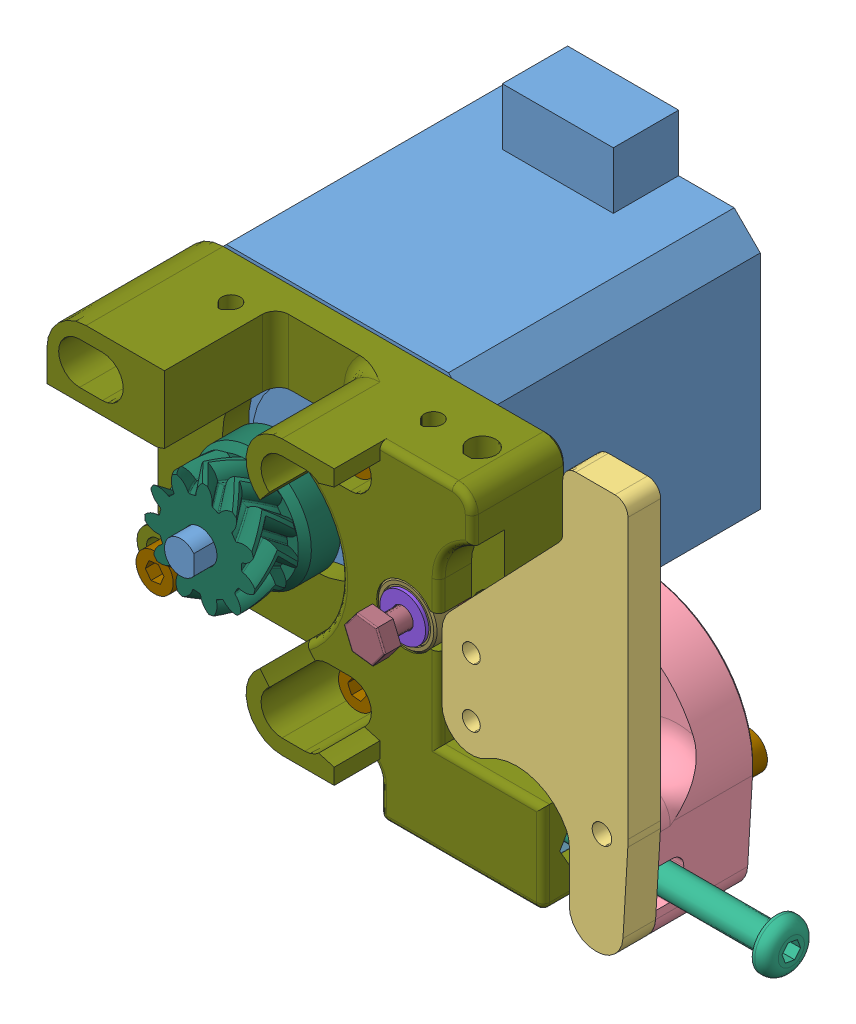
SolidWorks assembly extruder-drive, configuration Default. Lengths in mm.
Overall size (102.01 62 67.75).
27 component instances, 17 part files, 60 mates.
Components (placement in the parent):
- 408-1: 408 [Default] at (-0.1298 7.2239 -17.7265) x (0 -1 0) z (0 0 1) size (50.7 42 67.75)
- 279-1: 279 [Default] at (33.8857 6.1479 32.8235) x (0.656358 0.75445 0) z (0 0 -1) size (10 10 4)
- 1308-1: 1308 [lasercut] at (34.8702 7.2796 40.5235) x (1 0 0) z (0 0 -1) size (28.5 62 5)
- 1309-2: 1309 [Default] at (34.8702 7.2796 29.0235) x (1 0 0) z (0 0 -1) size (28.5 35.3 14.5)
- 1193-1: 1193 [Default] at (39.681 -14.7761 33.5235) x (0 0.866025 -0.5) z (1 0 0) size (8.08 7 3.2)
- 650-1: 650 [Default] at (74.681 -14.7761 33.5235) x (0 -0.641308 -0.767284) z (1 0 0) size (7.6 7.6 37.2)
- 1185-2: 1185 [Default] at (49.0702 -14.7761 33.5235) x (0 -0.672385 0.740201) z (1 0 0) size (9 9 0.8)
- 212-2: 212 [Default] at (34.8702 7.2796 35.8235) x (0.728607 0.684932 0) z (0 0 -1) size (7 7 0.5)
- 257-6: 257 [Default] at (34.8702 7.2796 21.0235) x (0.881615 -0.471969 0) z (0 0 -1) size (5.7 5.7 15)
- 1183-1: 1183 [Default] at (5.8702 7.2239 29.13) x (-1 0 0) z (0 -0.924225 -0.381849) size (4 3 3)
- 212-4: 212 [Default] at (24.8702 7.2239 26.1235) x (0.64125 0.767332 0) z (0 0 -1) size (7 7 0.5)
- 212-5: 212 [Default] at (34.8702 7.2796 31.3235) x (0.728607 0.684932 0) z (0 0 -1) size (7 7 0.5)
- 448-1: 448 [Default] at (24.8702 7.2239 30.1235) size (8.22 8.21 6.4)
- 423-2: 423 [Default] at (24.8702 7.2239 39.0235) x (0.994247 0.107114 0) z (0 0 1) size (9 9 4)
- 423-3: 423 [Default] at (24.8702 7.2239 28.6235) x (-0.824305 -0.566147 0) z (0 0 1) size (9 9 4)
- 113-1: 113 [Default] at (24.8702 7.2239 44.4235) x (-0.991951 0.126624 0) z (0 0 1) size (6.35 5.5 27.5)
- 204-1: 204 [Default] at (24.8702 7.2239 25.6235) x (0.98296 -0.183817 0) z (0 0 -1) size (6.35 5.5 4)
- 1310-4: 1310 [ISO - RH Helical gear 1M 17T 45HA 20PA 12FW ---17A75H50L0.8N] at (-0.1298 7.2239 43.5235) x (0 0 -1) z (0.449096 -0.893483 0) size (13 18 18)
- 1311-4: 1311 [ISO - RH Helical gear 1M 17T 45HA 20PA 12FW ---17A75H50L0.8N] at (24.8702 7.2239 47.0235) x (0 0 -1) z (0.991951 -0.126624 0) size (9 36.33 36.3) (hidden)
- 1306-1: 1306 [Default] at (-0.1298 7.2239 26.0235) x (0 -1 0) z (0 0 1) size (50 69 21.5)
- 257-7: 257 [Default] at (34.8702 -1.7204 21.0235) x (-0.999483 0.032148 0) z (0 0 -1) size (5.7 5.7 15)
- 257-8: 257 [Default] at (54.8702 -6.7204 21.0235) x (-0.827471 0.561509 0) z (0 0 -1) size (5.7 5.7 15)
- 257-9: 257 [Default] at (-15.6298 22.7239 35.5235) x (0.910936 0.412547 0) z (0 0 1) size (5.7 5.7 15)
- 257-10: 257 [Default] at (15.3702 -8.2761 35.5235) x (0.910936 0.412547 0) z (0 0 1) size (5.7 5.7 15)
- 257-11: 257 [Default] at (15.3702 22.7239 35.5235) x (0.910936 0.412547 0) z (0 0 1) size (5.7 5.7 15)
- 257-12: 257 [Default] at (-15.6298 -8.2761 35.5235) x (-0.129262 0.991611 0) z (0 0 1) size (5.7 5.7 15)
- 212-6: 212 [Default] at (24.8702 7.2239 41.0235) x (0.728607 0.684932 0) z (0 0 -1) size (7 7 0.5)
Mates (geometry in assembly coordinates):
- Concentric1: concentric aligned: cylinder of 408-1 through (-0.1298 7.2239 50.0235) axis (0 0 -1) radius 2.5; cylinder of 1310-4 through (-0.1298 7.2239 47.0235) axis (0 0 -1) radius 2.55
- Coincident59: coincident aligned: plane of 1310-4 through (-0.1298 7.2239 47.0235) normal (0 0 1); plane of 1311-4 through (24.8702 7.2239 47.0235) normal (0 0 1)
- Parallel9: parallel anti-aligned: plane of 113-1 through (26.7934 9.7507 46.9235) normal (0.126624 0.991951 0); plane of 1311-4 through (23.5989 10.2593 44.4235) normal (-0.126624 -0.991951 0)
- Concentric2: concentric aligned: cylinder of 113-1 through (24.8702 7.2239 19.4235) axis (0 0 1) radius 1.5; cylinder of 1311-4 through (24.8702 7.2239 41.0235) axis (0 0 1) radius 1.65
- Coincident61: coincident anti-aligned: plane of 113-1 through (24.8702 7.2239 44.4235) normal (0 0 -1); plane of 1311-4 through (24.8702 7.2239 44.4235) normal (0 0 1)
- Concentric3: concentric aligned: cylinder of 113-1 through (24.8702 7.2239 19.4235) axis (0 0 1) radius 1.5; cylinder of 204-1 through (24.8702 7.2239 23.2235) axis (0 0 1) radius 1.25
- Concentric5: concentric anti-aligned: cylinder of 423-2 through (24.8702 7.2239 41.5235) axis (0 0 -1) radius 1.5; cylinder of 113-1 through (24.8702 7.2239 19.4235) axis (0 0 1) radius 1.5
- Coincident67: coincident anti-aligned: plane of 423-2 through (27.1073 7.4649 40.5235) normal (0 0 1); plane of 212-6 through (24.8702 7.2239 40.5235) normal (0 0 -1)
- Concentric6: concentric anti-aligned: cylinder of 448-1 through (24.8702 7.2239 36.5235) axis (0 0 -1) radius 1.25; cylinder of 113-1 through (24.8702 7.2239 19.4235) axis (0 0 1) radius 1.5
- Coincident68: coincident anti-aligned: plane of 448-1 through (24.8702 7.2239 36.5235) normal (0 0 1); plane of 423-2 through (26.3616 7.3846 36.5235) normal (0 0 -1)
- Concentric7: concentric anti-aligned: cylinder of 423-3 through (24.8702 7.2239 31.1235) axis (0 0 -1) radius 1.5; cylinder of 113-1 through (24.8702 7.2239 19.4235) axis (0 0 1) radius 1.5
- Coincident69: coincident anti-aligned: plane of 448-1 through (24.8702 7.2239 30.1235) normal (0 0 -1); plane of 423-3 through (23.0155 5.9501 30.1235) normal (0 0 1)
- Concentric8: concentric aligned: cylinder of 212-4 through (24.8702 7.2239 25.6235) axis (0 0 1) radius 1.6; cylinder of 113-1 through (24.8702 7.2239 19.4235) axis (0 0 1) radius 1.5
- Coincident70: coincident anti-aligned: plane of 212-4 through (24.8702 7.2239 26.1235) normal (0 0 1); plane of 423-3 through (23.6338 6.3747 26.1235) normal (0 0 -1)
- Coincident71: coincident anti-aligned: plane of 212-4 through (24.8702 7.2239 25.6235) normal (0 0 -1); plane of 204-1 through (24.8702 7.2239 25.6235) normal (0 0 1)
- Coincident72: coincident anti-aligned: plane of 1308-1 through (45.8702 -10.7204 35.5235) normal (0 0 -1); plane of 1309-2 through (54.8702 -6.7204 35.5235) normal (0 0 1)
- Concentric9: concentric aligned: circle of 1308-1; cylinder of 257-8 through (54.8702 -6.7204 33.0235) axis (0 0 -1) radius 1.5
- Concentric18: concentric aligned: cylinder of 1309-2 through (34.8702 7.2796 22.5235) axis (0 0 -1) radius 3; cylinder of 257-6 through (34.8702 7.2796 33.0235) axis (0 0 -1) radius 1.5
- Coincident80: coincident anti-aligned: plane of 1309-2 through (34.8702 8.0796 21.0235) normal (0 0 -1); plane of 257-6 through (34.8702 7.2796 21.0235) normal (0 0 1)
- Concentric15: concentric anti-aligned: cylinder of 257-6 through (34.8702 7.2796 33.0235) axis (0 0 -1) radius 1.5; cylinder of 212-5 through (34.8702 7.2796 30.8235) axis (0 0 1) radius 1.6
- Concentric16: concentric anti-aligned: cylinder of 279-1 through (34.8702 7.2796 30.3235) axis (0 0 1) radius 1.5; cylinder of 257-6 through (34.8702 7.2796 33.0235) axis (0 0 -1) radius 1.5
- Coincident82: coincident anti-aligned: plane of 279-1 through (36.347 8.9771 31.3235) normal (0 0 -1); plane of 212-5 through (34.8702 7.2796 31.3235) normal (0 0 1)
- Parallel2: parallel anti-aligned: plane of 1308-1 through (45.8702 -10.7204 40.5235) normal (0 0 1); plane of 1311-4 through (24.8702 7.2239 41.0235) normal (0 0 -1)
- Concentric19: concentric anti-aligned: cylinder of 212-2 through (34.8702 7.2796 35.3235) axis (0 0 1) radius 1.6; cylinder of 257-6 through (34.8702 7.2796 33.0235) axis (0 0 -1) radius 1.5
- Coincident85: coincident anti-aligned: plane of 279-1 through (35.8547 8.4113 35.3235) normal (0 0 1); plane of 212-2 through (34.8702 7.2796 35.3235) normal (0 0 -1)
- Concentric20: concentric aligned: cylinder of 1308-1 through (34.8702 -1.7204 35.5235) axis (0 0 1) radius 1.375; cylinder of 1309-2 through (34.8702 -1.7204 21.0235) axis (0 0 1) radius 1.6
- Concentric23: concentric: cylinder of 1309-2 through (34.8702 -1.7204 21.0235) axis (0 0 1) radius 1.6; point of assembly
- Distance1: distance = 2 mm aligned: plane of 279-1 through (37.3316 10.1088 35.3235) normal (0 0 1); plane of assembly through (0 0 33.3235) normal (0 0 1)
- Concentric24: concentric aligned: cylinder of 1306-1 through (24.8702 7.2239 29.0235) axis (0 0 -1) radius 4.5; cylinder of 423-3 through (24.8702 7.2239 34.1235) axis (0 0 -1) radius 4.5
- Coincident94: coincident anti-aligned: plane of 1309-2 through (34.8702 7.2796 30.8235) normal (0 0 1); plane of 212-5 through (34.8702 7.2796 30.8235) normal (0 0 -1)
- Tangent1: tangent anti-aligned: plane of 1309-2 through (58.8702 -15.6922 31.5235) normal (0 0 1); cylinder of 650-1 through (39.681 -14.7761 33.5235) axis (1 0 0) radius 2
- Concentric25: concentric anti-aligned: cylinder of 650-1 through (39.681 -14.7761 33.5235) axis (1 0 0) radius 2; cylinder of 1185-2 through (49.8702 -14.7761 33.5235) axis (-1 0 0) radius 2.15
- Parallel6: parallel aligned: plane of 1309-2 through (49.8702 -10.7204 21.0235) normal (-1 0 0); plane of 650-1 through (74.681 -14.7761 33.5235) normal (-1 0 0)
- Coincident99: coincident anti-aligned: plane of 1309-2 through (49.8702 -10.7204 21.0235) normal (-1 0 0); plane of 1185-2 through (49.8702 -14.7761 33.5235) normal (1 0 0)
- Concentric26: concentric anti-aligned: cylinder of 1193-1 through (42.881 -14.7761 33.5235) axis (-1 0 0) radius 1.65; cylinder of 650-1 through (39.681 -14.7761 33.5235) axis (1 0 0) radius 2
- Coincident100: coincident aligned: plane of 1193-1 through (39.681 -14.7761 33.5235) normal (-1 0 0); plane of 650-1 through (39.681 -14.7761 33.5235) normal (-1 0 0)
- Parallel8: parallel anti-aligned: plane of 1185-2 through (49.0702 -14.7761 33.5235) normal (-1 0 0); plane of 1306-1 through (45.8702 1.7239 40.5235) normal (1 0 0)
- Concentric27: concentric anti-aligned: cylinder of 1309-2 through (34.8702 -1.7204 21.0235) axis (0 0 1) radius 1.6; cylinder of 257-7 through (34.8702 -1.7204 33.0235) axis (0 0 -1) radius 1.5
- Coincident109: coincident anti-aligned: plane of 257-7 through (34.8702 -1.7204 21.0235) normal (0 0 1); plane of 1309-2 through (34.8702 8.0796 21.0235) normal (0 0 -1)
- Concentric28: concentric anti-aligned: cylinder of 1309-2 through (54.8702 -6.7204 21.0235) axis (0 0 1) radius 1.375; cylinder of 257-8 through (54.8702 -6.7204 33.0235) axis (0 0 -1) radius 1.5
- Coincident110: coincident anti-aligned: plane of 1309-2 through (34.8702 8.0796 21.0235) normal (0 0 -1); plane of 257-8 through (54.8702 -6.7204 21.0235) normal (0 0 1)
- Coincident112: coincident anti-aligned: plane of 1306-1 through (34.9505 7.2239 35.5235) normal (0 0 1); plane of 257-10 through (15.3702 -8.2761 35.5235) normal (0 0 -1)
- Coincident113: coincident anti-aligned: plane of 1306-1 through (34.9505 7.2239 35.5235) normal (0 0 1); plane of 257-9 through (-15.6298 22.7239 35.5235) normal (0 0 -1)
- Coincident114: coincident anti-aligned: plane of 1306-1 through (34.9505 7.2239 35.5235) normal (0 0 1); plane of 257-11 through (15.3702 22.7239 35.5235) normal (0 0 -1)
- Coincident115: coincident anti-aligned: plane of 1306-1 through (34.9505 7.2239 35.5235) normal (0 0 1); plane of 257-12 through (-15.6298 -8.2761 35.5235) normal (0 0 -1)
- Coincident116: coincident aligned: circle of 408-1; cylinder of 257-11 through (15.3702 22.7239 23.5235) axis (0 0 1) radius 1.5
- Coincident117: coincident aligned: circle of 408-1; cylinder of 257-9 through (-15.6298 22.7239 23.5235) axis (0 0 1) radius 1.5
- Concentric29: concentric aligned: cylinder of 408-1 through (15.3702 -8.2761 21.0235) axis (0 0 1) radius 1.5; cylinder of 257-10 through (15.3702 -8.2761 23.5235) axis (0 0 1) radius 1.5
- Concentric30: concentric aligned: cylinder of 408-1 through (-15.6298 -8.2761 21.0235) axis (0 0 1) radius 1.5; cylinder of 257-12 through (-15.6298 -8.2761 23.5235) axis (0 0 1) radius 1.5
- Coincident118: coincident aligned: plane of 408-1 through (16.8772 -13.7761 26.0235) normal (0 -1 0); plane of 1306-1 through (-21.1298 -13.7761 29.0235) normal (0 -1 0)
- Width1: width anti-aligned: plane of 1306-1 through (35.8702 -11.1761 31.7451) normal (0 -1 0); plane of 1306-1 through (35.8702 -18.3761 35.902) normal (0 1 0); plane of 1193-1 through (42.881 -11.2761 31.5028) normal (0 1 0); plane of 1193-1 through (42.881 -18.2761 35.5443) normal (0 -1 0)
- Coincident119: coincident: plane of 448-1 through (24.8702 7.2239 33.3235) normal (0 0 -1); line of 1306-1 through (29.3317 -14.7761 33.3235) axis (0 1 0)
- Coincident121: coincident anti-aligned: plane of 408-1 through (-0.1298 7.2239 26.0235) normal (0 0 1); plane of 1306-1 through (24.8702 7.2239 26.0235) normal (0 0 -1)
- Concentric31: concentric aligned: cylinder of 423-2 through (24.8702 7.2239 41.5235) axis (0 0 -1) radius 4.5; cylinder of 1306-1 through (24.8702 7.2239 40.5235) axis (0 0 -1) radius 4.5
- Concentric32: concentric aligned: cylinder of 1306-1 through (34.8702 -1.7204 47.5235) axis (0 0 -1) radius 1.5; cylinder of 257-7 through (34.8702 -1.7204 33.0235) axis (0 0 -1) radius 1.5
- Coincident122: coincident anti-aligned: plane of 408-1 through (-0.1298 7.2239 26.0235) normal (0 0 1); plane of 1306-1 through (34.9505 7.2239 26.0235) normal (0 0 -1)
- Parallel10: parallel aligned: plane of 408-1 through (16.8772 28.2239 26.0235) normal (0 1 0); plane of 1306-1 through (20.8702 28.2239 40.5235) normal (0 1 0)
- Concentric33: concentric anti-aligned: cylinder of 650-1 through (39.681 -14.7761 33.5235) axis (1 0 0) radius 2; cylinder of ? through (74.2655 -14.7761 33.5235) axis (-1 0 0) radius 1.65
- Coincident123: coincident anti-aligned: plane of 1311-4 through (24.8702 7.2239 41.0235) normal (0 0 -1); plane of 212-6 through (24.8702 7.2239 41.0235) normal (0 0 1)
- Concentric34: concentric aligned: cylinder of 113-1 through (24.8702 7.2239 19.4235) axis (0 0 1) radius 1.5; cylinder of 212-6 through (24.8702 7.2239 40.5235) axis (0 0 1) radius 1.6
